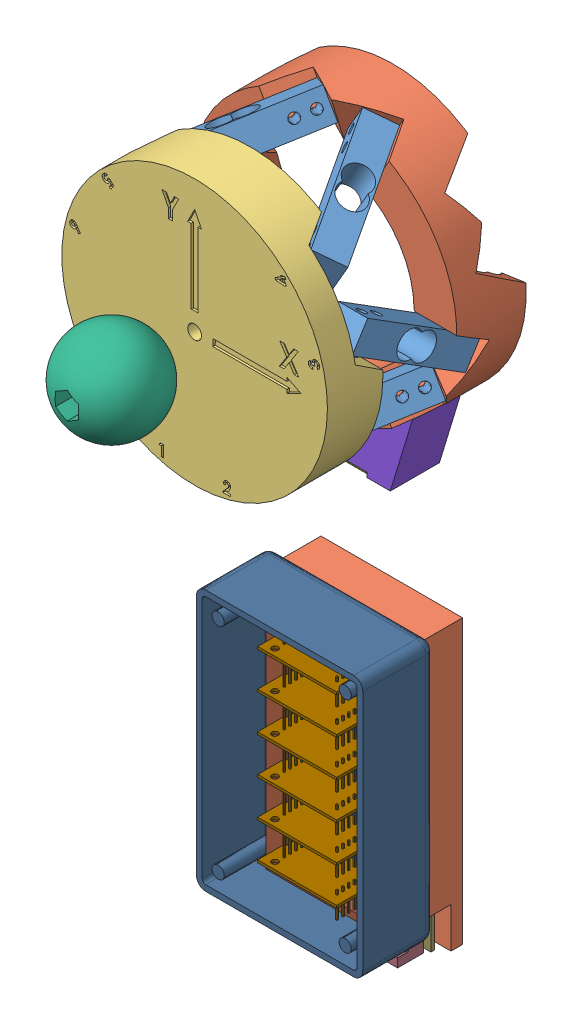
SolidWorks assembly Capteur 6 axes V4, configuration Défaut. Lengths in mm.
Overall size (115 321.14 141.36).
49 component instances, 21 part files, 42 mates.
Components (placement in the parent):
- Cellule_2kg-1: Cellule_2kg [Défaut] at (46.7654 0 43) x (1 0 0) z (0 -0.531768 -0.84689) size (12.7 12.7 58)
- Cellule_2kg-2: Cellule_2kg [Défaut] at (23.3827 40.5 43) x (0.5 0.866025 0) z (0.460525 -0.265884 0.84689) size (12.7 12.7 58)
- Cellule_2kg-3: Cellule_2kg [Défaut] at (-23.3827 40.5 43) x (0.5 -0.866025 0) z (-0.460525 -0.265884 0.84689) size (12.7 12.7 58)
- Cellule_2kg-4: Cellule_2kg [Défaut] at (-46.7654 0 43) x (1 0 0) z (0 -0.531768 -0.84689) size (12.7 12.7 58)
- Cellule_2kg-5: Cellule_2kg [Défaut] at (-23.3827 -40.5 43) x (0.5 0.866025 0) z (0.460525 -0.265884 0.84689) size (12.7 12.7 58)
- Cellule_2kg-6: Cellule_2kg [Défaut] at (23.3827 -40.5 43) x (0.5 -0.866025 0) z (-0.460525 -0.265884 0.84689) size (12.7 12.7 58)
- Bâti-1: Bâti [Défaut] at origin size (115 115 30)
- Socle-1: Socle [Défaut] at origin size (115 115 24)
- Bille-1: Bille [Défaut] at (26.8144 38.5187 65.0132) x (-0.007042 0.551582 0.834091) z (-0.90906 -0.351035 0.224463) size (4 4 4)
- Bille-2: Bille [Défaut] at (46.7654 3.9627 65.0132) x (0.190315 -0.800087 -0.568895) z (0.705854 -0.291233 0.645719) size (4 4 4)
- Bille-3: Bille [Défaut] at (-26.8144 38.5187 65.0132) x (0.688654 0.348386 0.635911) z (-0.205198 -0.747521 0.631749) size (4 4 4)
- Bille-4: Bille [Défaut] at (-19.9509 -42.4813 65.0132) x (0.820926 0.267797 0.504346) z (-0.554219 0.160892 0.816673) size (4 4 4)
- Bille-5: Bille [Défaut] at (-46.7654 3.9627 65.0132) x (-0.161243 0.532713 0.830793) z (-0.878 -0.46185 0.125738) size (4 4 4)
- Bille-6: Bille [Défaut] at (19.9509 -42.4813 65.0132) x (0.704958 0.000759 0.709248) z (-0.641285 0.427843 0.636949) size (4 4 4)
- hex thin nut chamfered gradeab_iso-1: hex thin nut chamfered gradeab_iso [Hexagon Thin Nut ISO - 4035 - M6 - N] at (0 0 79) size (10 11.55 3.2)
- Poignée-1: Poignée [Défaut] at (0 0 122) x (1 0 0) z (0 -1 0) size (40 35.36 40)
- VGA PORT-1: VGA PORT [По умолчанию] at (0 -80 12) x (-1 0 0) z (0 1 0) size (30.8 16.47 13.4)
- BoitierConnecteur-1: BoitierConnecteur [Défaut] at origin size (60 32.95 21.27)
- Boitier_electronique^Capteur 6 axes V4-1: Boitier_electronique^Capteur 6 axes V4 [Défaut] at origin size (72 132.5 49.2) (virtual)
  - Boitier-1: Boitier [Défaut] at (0 -187.6392 18) x (-1 0 0) z (0 1 0) size (72 31.2 113)
    - Capteur_HX711^Boitier-1: Capteur_HX711^Boitier [Défaut] at (17 13.2 -42) x (0 1 0) z (0 0 1) size (21 34.2 17.7) (virtual)
    - Capteur_HX711^Boitier-7: Capteur_HX711^Boitier [Défaut] at (17 13.2 -26) x (0 1 0) z (0 0 1) size (21 34.2 17.7) (virtual)
    - Capteur_HX711^Boitier-8: Capteur_HX711^Boitier [Défaut] at (17 13.2 -10) x (0 1 0) z (0 0 1) size (21 34.2 17.7) (virtual)
    - Capteur_HX711^Boitier-9: Capteur_HX711^Boitier [Défaut] at (17 13.2 6) x (0 1 0) z (0 0 1) size (21 34.2 17.7) (virtual)
    - Capteur_HX711^Boitier-10: Capteur_HX711^Boitier [Défaut] at (17 13.2 22) x (0 1 0) z (0 0 1) size (21 34.2 17.7) (virtual)
    - Capteur_HX711^Boitier-11: Capteur_HX711^Boitier [Défaut] at (17 13.2 38) x (0 1 0) z (0 0 1) size (21 34.2 17.7) (virtual)
    - Boitier^Boitier-1: Boitier^Boitier [Défaut] x (0 0 -1) z (1 0 0) size (113 31.2 72) (virtual)
    - Rack^Boitier-1: Rack^Boitier [Défaut] at origin size (49 10 107.6) (virtual)
  - User Library-Arduino-UNO-1: User Library-Arduino-UNO [Predeterminado] at (-0.65 -216.3547 12.5325) x (0 1 0) z (1 0 0) size (74.65 14.9 53.3)
    - User Library-Arduino-UNO_Arduino_UNO_PCB-1: User Library-Arduino-UNO_Arduino_UNO_PCB [Predeterminado] at (-41.2845 -4.4325 26.65) size (68.65 6.6 53.3)
    - User Library-Arduino-UNO_User Library-Arduino Mega_DC POWER JACK-1: User Library-Arduino-UNO_User Library-Arduino Mega_DC POWER JACK [Default] at (-43.2845 -2.8325 18.828) x (0 0 1) z (-1 0 0) size (9.47 14.78 14.48)
    - User Library-Arduino-UNO_User Library-Arduino Mega_USB SM host-1: User Library-Arduino-UNO_User Library-Arduino Mega_USB SM host [Default] at (-39.0345 2.4175 -12.65) x (0 0 1) z (-1 0 0) size (14.86 14.22 16.5)
    - User Library-Arduino-UNO_User Library-Arduino Mega_tactile BUTTON-1: User Library-Arduino-UNO_User Library-Arduino Mega_tactile BUTTON [Default] at (15.2655 -2.8325 -1.55) x (1 0 0) z (0 1 0) size (7.9 6.2 7.35)
    - User Library-Arduino-UNO_User Library-Arduino Mega_Header Vertical 2_54mm Pitch4-1-3: User Library-Arduino-UNO_User Library-Arduino Mega_Header Vertical 2_54mm Pitch4-1 [2 Way] at (-21.2045 -2.8325 -20.11) size (2.54 9.3 5.08)
    - User Library-Arduino-UNO_User Library-Arduino Mega_Header Vertical 2_54mm Pitch4-1-4: User Library-Arduino-UNO_User Library-Arduino Mega_Header Vertical 2_54mm Pitch4-1 [2 Way] at (-23.7445 -2.8325 -20.11) size (2.54 9.3 5.08)
    - User Library-Arduino-UNO_User Library-Arduino Mega_Header Vertical 2_54mm Pitch4-1-5: User Library-Arduino-UNO_User Library-Arduino Mega_Header Vertical 2_54mm Pitch4-1 [2 Way] at (-26.2845 -2.8325 -20.11) size (2.54 9.3 5.08)
    - User Library-Arduino-UNO_User Library-Arduino Mega_Header Vertical 2_54mm Pitch4-1-6: User Library-Arduino-UNO_User Library-Arduino Mega_Header Vertical 2_54mm Pitch4-1 [2 Way] at (24.3255 -2.8325 -3.11) x (0 0 -1) z (1 0 0) size (2.54 9.3 5.08)
    - User Library-Arduino-UNO_User Library-Arduino Mega_Header Vertical 2_54mm Pitch4-1-7: User Library-Arduino-UNO_User Library-Arduino Mega_Header Vertical 2_54mm Pitch4-1 [2 Way] at (24.3255 -2.8325 1.97) x (0 0 -1) z (1 0 0) size (2.54 9.3 5.08)
    - User Library-Arduino-UNO_User Library-Arduino Mega_Header Vertical 2_54mm Pitch4-1-8: User Library-Arduino-UNO_User Library-Arduino Mega_Header Vertical 2_54mm Pitch4-1 [2 Way] at (24.3255 -2.8325 -0.57) x (0 0 -1) z (1 0 0) size (2.54 9.3 5.08)
    - User Library-Arduino-UNO_User Library-Arduino Mega_PIN HEADER FEMALE 6-1: User Library-Arduino-UNO_User Library-Arduino Mega_PIN HEADER FEMALE 6 [Default] at (-7.3445 -2.8325 24.38) size (15.24 8.3 2.54)
    - User Library-Arduino-UNO_User Library-Arduino Mega_PIN HEADER FEMALE 6-2: User Library-Arduino-UNO_User Library-Arduino Mega_PIN HEADER FEMALE 6 [Default] at (9.8955 -2.8325 24.38) size (15.24 8.3 2.54)
    - User Library-Arduino-UNO_User Library-Arduino Mega_PIN HEADER FEMALE 8-1: User Library-Arduino-UNO_User Library-Arduino Mega_PIN HEADER FEMALE 8 [Default] at (-17.5745 -2.8325 -24.38) size (20.32 8.3 2.54)
    - User Library-Arduino-UNO_User Library-Arduino Mega_PIN HEADER FEMALE 8-2: User Library-Arduino-UNO_User Library-Arduino Mega_PIN HEADER FEMALE 8 [Default] at (3.7455 -2.8325 -24.38) size (20.32 8.3 2.54)
    - User Library-Arduino-UNO_User Library-28 pin dip-1: User Library-Arduino-UNO_User Library-28 pin dip [Default] at (1.315 2.5165 10.213) x (0 0 -1) z (1 0 0) size (7.87 6.22 35.94)
  - Boitier Arduino-1: Boitier Arduino [Défaut] at origin size (61.3 122.5 18)
  - hex bolt gradeab_iso-1: hex bolt gradeab_iso [ISO 4014 - M3 x 25 x 25-N] at (24 -182.9892 1) x (0 0 1) z (-0.99465 0.103304 0) size (27 6.35 5.5)
  - hex bolt gradeab_iso-2: hex bolt gradeab_iso [ISO 4014 - M3 x 25 x 25-N] at (-25.3 -146.1392 1) x (0 0 1) z (-0.99465 0.103304 0) size (27 6.35 5.5)
  - hex bolt gradeab_iso-3: hex bolt gradeab_iso [ISO 4014 - M3 x 25 x 25-N] at (-25.3 -182.9892 1) x (0 0 1) z (-0.99465 0.103304 0) size (27 6.35 5.5)
  - hex bolt gradeab_iso-4: hex bolt gradeab_iso [ISO 4014 - M3 x 25 x 25-N] at (24 -146.1392 1) x (0 0 1) z (-0.99465 0.103304 0) size (27 6.35 5.5)
Mates (geometry in assembly coordinates):
- Coïncidente1: coincident anti-aligned: line of Cellule_2kg-1 through (46.7654 17.2559 70.4816) axis (0 -0.531768 -0.84689); line of assembly
- Coïncidente2: coincident: point of Cellule_2kg-1; plane of assembly
- Coïncidente3: coincident anti-aligned: line of Cellule_2kg-2 through (8.4387 49.1279 15.5184) axis (0.460525 -0.265884 0.84689); line of assembly
- Coïncidente4: coincident: point of Cellule_2kg-2; plane of assembly
- Coïncidente5: coincident aligned: line of Cellule_2kg-3 through (-8.4387 49.1279 15.5184) axis (-0.460525 -0.265884 0.84689); line of assembly
- Coïncidente6: coincident: point of Cellule_2kg-3; plane of assembly
- Coïncidente7: coincident aligned: line of Cellule_2kg-4 through (-46.7654 17.2559 70.4816) axis (0 -0.531768 -0.84689); line of assembly
- Coïncidente8: coincident: point of Cellule_2kg-4; plane of assembly
- Coïncidente9: coincident aligned: line of Cellule_2kg-5 through (-38.3267 -31.8721 15.5184) axis (0.460525 -0.265884 0.84689); line of assembly
- Coïncidente10: coincident: point of Cellule_2kg-5; plane of assembly
- Coïncidente11: coincident anti-aligned: line of Cellule_2kg-6 through (38.3267 -31.8721 15.5184) axis (-0.460525 -0.265884 0.84689); line of assembly
- Coïncidente12: coincident: point of Cellule_2kg-6; plane of assembly
- Coïncidente15: coincident: line of Cellule_2kg-1 through (57.4904 0 43) axis (-1 0 0); point of assembly
- Coïncidente16: coincident: line of Cellule_2kg-2 through (28.7452 49.7881 43) axis (-0.5 -0.866025 0); point of assembly
- Coïncidente17: coincident: line of Cellule_2kg-3 through (-18.0202 31.2119 43) axis (-0.5 0.866025 0); point of assembly
- Coïncidente18: coincident: line of Cellule_2kg-4 through (-36.0404 0 43) axis (-1 0 0); point of assembly
- Coïncidente19: coincident: line of Cellule_2kg-5 through (-18.0202 -31.2119 43) axis (-0.5 -0.866025 0); point of assembly
- Coïncidente20: coincident: line of Cellule_2kg-6 through (28.7452 -49.7881 43) axis (-0.5 0.866025 0); point of assembly
- Coïncidente21: coordinate: point of Bâti-1; point of Socle-1
- Coïncidente22: coincident: point of Bille-1; line of assembly
- Tangent1: tangent anti-aligned: plane of Cellule_2kg-2 through (2.1952 45.4003 21.8169) normal (-0.733428 0.423445 0.531768); sphere of Bille-1
- Coïncidente23: coincident: point of Bille-2; line of assembly
- Coïncidente24: coincident: point of Bille-3; line of assembly
- Tangent2: tangent anti-aligned: plane of Cellule_2kg-1 through (40.4154 10.0435 70.9365) normal (0 -0.84689 0.531768); sphere of Bille-2
- Tangent3: tangent anti-aligned: plane of Cellule_2kg-3 through (-8.5452 56.3988 21.8169) normal (0.733428 0.423445 0.531768); sphere of Bille-3
- Coïncidente25: coincident: point of Bille-5; line of assembly
- Coïncidente26: coincident: point of Bille-4; line of assembly
- Coïncidente27: coincident: point of Bille-6; line of assembly
- Tangent5: tangent anti-aligned: plane of Cellule_2kg-4 through (-53.1154 10.0435 70.9365) normal (0 -0.84689 0.531768); sphere of Bille-5
- Tangent6: tangent anti-aligned: plane of Cellule_2kg-5 through (-44.5702 -35.5997 21.8169) normal (-0.733428 0.423445 0.531768); sphere of Bille-4
- Tangent7: tangent anti-aligned: plane of Cellule_2kg-6 through (38.2202 -24.6012 21.8169) normal (0.733428 0.423445 0.531768); sphere of Bille-6
- Coaxiale1: concentric aligned: cylinder of Socle-1 through (0 0 74) axis (0 0 1) radius 3; cylinder of hex thin nut chamfered gradeab_iso-1 through (0 0 75.8) axis (0 0 1) radius 2.5
- Coïncidente28: coincident aligned: plane of hex thin nut chamfered gradeab_iso-1 through (0 0 79) normal (0 1 0); plane of assembly through (0 0 0) normal (0 1 0)
- Coïncidente29: coincident anti-aligned: plane of Socle-1 through (0 0 79) normal (0 0 -1); plane of hex thin nut chamfered gradeab_iso-1 through (0 5.7735 79) normal (0 0 1)
- Coïncidente31: coordinate: unknown of ?
- Coaxiale2: concentric aligned: cylinder of Socle-1 through (0 0 74) axis (0 0 1) radius 3; cylinder of Poignée-1 through (0 0 102) axis (0 0 1) radius 3
- Distance1: distance = 20 mm anti-aligned: plane of Socle-1 through (0 0 86) normal (0 0 1); plane of Poignée-1 through (31.7269 -89.7354 106) normal (0 0 -1)
- Coïncidente32: coincident anti-aligned: plane of VGA PORT-1; plane of assembly through (0 0 0) normal (1 0 0)
- Distance2: distance = 12 mm aligned: plane of VGA PORT-1; plane of assembly through (0 0 0) normal (0 0 1)
- Distance3: distance = 80 mm aligned: plane of VGA PORT-1 through (0 -80 12) normal (0 1 0); plane of assembly through (0 0 0) normal (0 1 0)
- Coïncidente42: coincident anti-aligned: plane of Boitier_electronique^Capteur 6 axes V4-1/Boitier-1/Rack^Boitier-1; plane of assembly through (0 0 0) normal (1 0 0)
- Distance7: distance = 18 mm aligned: plane of Boitier_electronique^Capteur 6 axes V4-1/Boitier-1/Boitier^Boitier-1 through (0 -187.6392 18) normal (0 0 -1); plane of Bâti-1 through (0 0 0) normal (0 0 -1)
